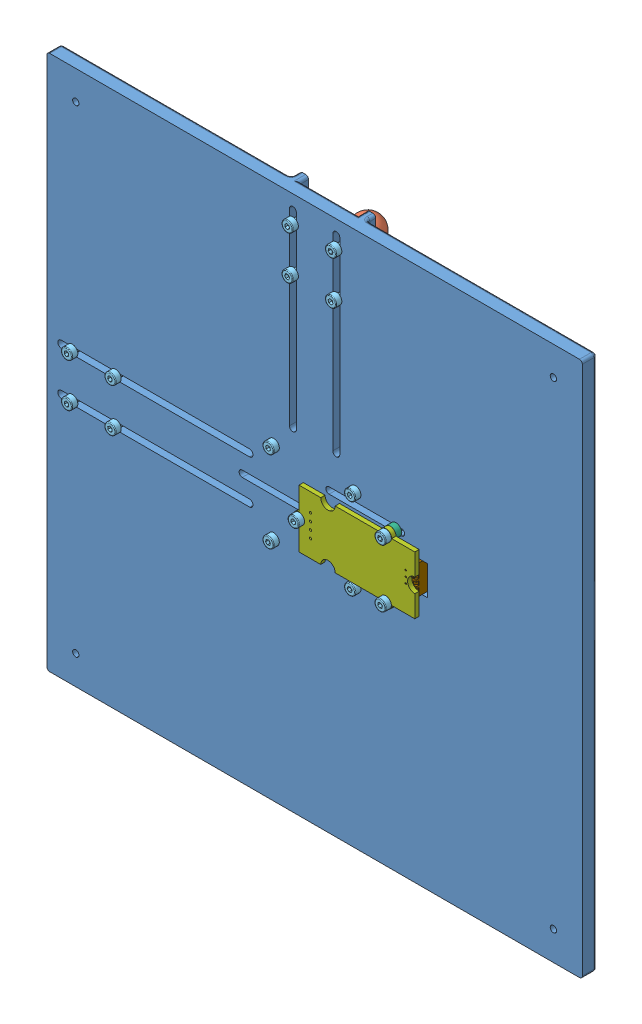
SolidWorks assembly plateau-complet, configuration Défaut. Lengths in mm.
Overall size (185 185 29.5).
45 component instances, 9 part files, 117 mates.
Components (placement in the parent):
- plateau-1: plateau [Défaut] at (22.8083 8.2939 197.5) size (185 185 8)
- support-sphere-ecrou_m2-4: support-sphere-ecrou_m2 [Défaut] at (-53.3917 8.2939 184.1699) x (0 -1 0) z (1 0 0) size (20 18.33 20)
- support-sphere-ecrou_m2-3: support-sphere-ecrou_m2 [Défaut] at (22.8083 84.4939 184.1699) x (1 0 0) z (0 1 0) size (20 18.33 20)
- support-fourchette-ecrou_m2-large-1: support-fourchette-ecrou_m2-large [Défaut] at (22.8083 8.2939 183.5) x (1 0 0) z (0 1 0) size (35 19 35)
- ecrou-h-6: ecrou-h [6007 HU M2] at (30.3083 91.9939 195.1) x (0.866025 -0.5 0) z (-0.5 -0.866025 0) size (4 1.6 4.62)
- ecrou-h-7: ecrou-h [6007 HU M2] at (15.3083 76.9939 195.1) x (0 1 0) z (1 0 0) size (4 1.6 4.62)
- ecrou-h-8: ecrou-h [6007 HU M2] at (30.3083 76.9939 195.1) x (0.866025 0.5 0) z (0.5 -0.866025 0) size (4 1.6 4.62)
- ecrou-h-9: ecrou-h [6007 HU M2] at (15.3083 91.9939 195.1) x (-0.866025 -0.5 0) z (-0.5 0.866025 0) size (4 1.6 4.62)
- ecrou-h-10: ecrou-h [6007 HU M2] at (-60.8917 15.7939 195.1) x (0.5 0.866025 0) z (0.866025 -0.5 0) size (4 1.6 4.62)
- ecrou-h-11: ecrou-h [6007 HU M2] at (-60.8917 0.7939 195.1) x (0.5 0.866025 0) z (0.866025 -0.5 0) size (4 1.6 4.62)
- ecrou-h-12: ecrou-h [6007 HU M2] at (-45.8917 0.7939 195.1) x (-0.5 -0.866025 0) z (-0.866025 0.5 0) size (4 1.6 4.62)
- ecrou-h-13: ecrou-h [6007 HU M2] at (-45.8917 15.7939 195.1) x (-0.5 0.866025 0) z (0.866025 0.5 0) size (4 1.6 4.62)
- vis-chc-15: vis-chc [Vis CHC M2x12] at (-45.8917 0.7939 202.5) x (0.832658 0.553787 0) z (0.553787 -0.832658 0) size (3.8 14 3.8)
- vis-chc-16: vis-chc [Vis CHC M2x12] at (-45.8917 15.7939 202.5) x (0.872712 0.488236 0) z (0.488236 -0.872712 0) size (3.8 14 3.8)
- vis-chc-17: vis-chc [Vis CHC M2x12] at (-60.8917 0.7939 202.5) x (0.878735 -0.477309 0) z (-0.477309 -0.878735 0) size (3.8 14 3.8)
- vis-chc-18: vis-chc [Vis CHC M2x12] at (-60.8917 15.7939 202.5) x (-0.020688 -0.999786 0) z (-0.999786 0.020688 0) size (3.8 14 3.8)
- vis-chc-19: vis-chc [Vis CHC M2x12] at (15.3083 76.9939 202.5) x (-0.459945 -0.887947 0) z (-0.887947 0.459945 0) size (3.8 14 3.8)
- vis-chc-20: vis-chc [Vis CHC M2x12] at (30.3083 76.9939 202.5) x (-0.307246 0.95163 0) z (0.95163 0.307246 0) size (3.8 14 3.8)
- vis-chc-21: vis-chc [Vis CHC M2x12] at (15.3083 91.9939 202.5) x (0.103271 -0.994653 0) z (-0.994653 -0.103271 0) size (3.8 14 3.8)
- vis-chc-22: vis-chc [Vis CHC M2x12] at (30.3083 91.9939 202.5) x (0.948564 0.316586 0) z (0.316586 -0.948564 0) size (3.8 14 3.8)
- vis-chc-23: vis-chc [Vis CHC M2x12] at (8.7083 22.3939 202.5) x (0.719096 0.694911 0) z (0.694911 -0.719096 0) size (3.8 14 3.8)
- vis-chc-24: vis-chc [Vis CHC M2x12] at (36.9083 22.3939 202.5) x (0.587191 0.809448 0) z (0.809448 -0.587191 0) size (3.8 14 3.8)
- vis-chc-25: vis-chc [Vis CHC M2x12] at (8.7083 -5.8061 202.5) x (0.239044 0.971009 0) z (0.971009 -0.239044 0) size (3.8 14 3.8)
- vis-chc-26: vis-chc [Vis CHC M2x12] at (36.9083 -5.8061 202.5) x (0.971464 0.237189 0) z (0.237189 -0.971464 0) size (3.8 14 3.8)
- ecrou-h-14: ecrou-h [6007 HU M2] at (8.7083 22.3939 195.16) x (0.866025 -0.5 0) z (-0.5 -0.866025 0) size (4 1.6 4.62)
- ecrou-h-15: ecrou-h [6007 HU M2] at (8.7083 -5.8061 195.16) x (0.866025 -0.5 0) z (-0.5 -0.866025 0) size (4 1.6 4.62)
- ecrou-h-16: ecrou-h [6007 HU M2] at (36.9083 -5.8061 195.16) x (0.866025 -0.5 0) z (-0.5 -0.866025 0) size (4 1.6 4.62)
- ecrou-h-17: ecrou-h [6007 HU M2] at (36.9083 22.3939 195.16) x (-0.866025 0.5 0) z (0.5 0.866025 0) size (4 1.6 4.62)
- ecrou-h-18: ecrou-h [6007 HU M2] at (-59.6917 90.7939 200.5) x (0.866025 0.5 0) z (0.5 -0.866025 0) size (4 1.6 4.62)
- ecrou-h-19: ecrou-h [6007 HU M2] at (105.3083 90.7939 198.9) x (0.866025 0.5 0) z (-0.5 0.866025 0) size (4 1.6 4.62)
- ecrou-h-20: ecrou-h [6007 HU M2] at (-59.6917 -74.2061 200.5) x (0 -1 0) z (-1 0 0) size (4 1.6 4.62)
- ecrou-h-21: ecrou-h [6007 HU M2] at (105.3083 -74.2061 200.5) x (0 1 0) z (1 0 0) size (4 1.6 4.62)
- vis-chc-30: vis-chc [Vis CHC M2x8] at (50.9161 18.1939 206) x (-0.221467 -0.975168 0) z (-0.975168 0.221467 0) size (3.8 10 3.8)
- vis-chc-32: vis-chc [Vis CHC M2x8] at (50.9161 -1.8061 206) x (-0.923728 -0.383049 0) z (-0.383049 0.923728 0) size (3.8 10 3.8)
- vis-chc-33: vis-chc [Vis CHC M2x8] at (20.9161 8.1939 206) x (-0.787107 -0.616816 0) z (-0.616816 0.787107 0) size (3.8 10 3.8)
- ecrou-h-24: ecrou-h [6007 HU M2] at (20.9161 8.1939 197.9) x (0 -1 0) z (1 0 0) size (4 1.6 4.62)
- ecrou-h-25: ecrou-h [6007 HU M2] at (50.9161 -1.8061 197.9) x (0.866025 0.5 0) z (-0.5 0.866025 0) size (4 1.6 4.62)
- ecrou-h-26: ecrou-h [6007 HU M2] at (50.9161 18.1939 197.9) x (-0.866025 0.5 0) z (-0.5 -0.866025 0) size (4 1.6 4.62)
- entretoise-grove-1: entretoise-grove [Défaut] at (50.9161 18.1939 202.5) x (0.992185 0.124776 0) z (0 0 1) size (4 4 2)
- entretoise-grove-2: entretoise-grove [Défaut] at (20.9161 8.1939 202.5) x (0.16979 0.98548 0) z (0 0 1) size (4 4 2)
- entretoise-grove-3: entretoise-grove [Défaut] at (50.9161 -1.8061 202.5) x (0.064788 0.997899 0) z (0 0 1) size (4 4 2)
- Grove IMU - droit-1: Grove IMU - droit [Défaut] at (42.9373 5.7987 163.25) x (0 -1 0) z (0 0 1) size (24 42 9.5)
  - Grove IMU Board-1: Grove IMU Board [Défaut] at (-2.3952 -22.0212 41.25) size (24 42 1.5)
  - MPU9150-1: MPU9150 [Défaut] at (-3.0078 -7.8003 40.45) size (4 4 0.8)
  - Connecteur Grove - droit-1: Connecteur Grove - droit [Défaut] at (-2.3952 11.9788 41.25) x (-1 0 0) z (0 -1 0) size (10 11 5)
Mates (geometry in assembly coordinates):
- Coïncidente5: coincident anti-aligned: plane of plateau-1 through (22.8083 8.2939 197.5) normal (0 0 -1); plane of support-sphere-ecrou_m2-4 through (-53.3917 8.2939 197.5) normal (0 0 1)
- Coïncidente8: coincident anti-aligned: plane of plateau-1 through (22.8083 8.2939 197.5) normal (0 0 -1); plane of support-sphere-ecrou_m2-3 through (22.8083 84.4939 197.5) normal (0 0 1)
- Coïncidente12: coincident anti-aligned: plane of plateau-1 through (22.8083 8.2939 197.5) normal (0 0 -1); plane of support-fourchette-ecrou_m2-large-1 through (22.8083 8.2939 197.5) normal (0 0 1)
- Coaxiale9: concentric anti-aligned: cylinder of support-sphere-ecrou_m2-3 through (30.3083 91.9939 197.501) axis (0 0 -1) radius 1.1; cylinder of ecrou-h-m2-6 through (30.3083 91.9939 193.5) axis (0 0 1) radius 0.7835
- Coïncidente26: coincident anti-aligned: plane of support-sphere-ecrou_m2-3 through (22.8083 84.4939 195.1) normal (0 0 -1); plane of ecrou-h-m2-6 through (32.6177 91.9939 195.1) normal (0 0 1)
- Parallèle1: parallel anti-aligned: plane of support-sphere-ecrou_m2-3 through (27.9783 91.9939 195.1) normal (0.866025 -0.5 0); plane of ecrou-h-m2-6 through (29.1536 93.9939 193.5) normal (-0.866025 0.5 0)
- Coaxiale10: concentric anti-aligned: cylinder of support-sphere-ecrou_m2-3 through (15.3083 91.9939 197.501) axis (0 0 -1) radius 1.1; cylinder of ecrou-h-m2-9 through (15.3083 91.9939 193.5) axis (0 0 1) radius 0.7835
- Parallèle2: parallel anti-aligned: plane of support-sphere-ecrou_m2-3 through (14.1433 94.0118 195.1) normal (0 -1 0); plane of ecrou-h-m2-9 through (16.463 93.9939 193.5) normal (0 1 0)
- Coïncidente29: coincident anti-aligned: plane of support-sphere-ecrou_m2-3 through (22.8083 84.4939 195.1) normal (0 0 -1); plane of ecrou-h-m2-9 through (16.463 89.9939 195.1) normal (0 0 1)
- Coaxiale11: concentric anti-aligned: cylinder of support-sphere-ecrou_m2-3 through (15.3083 76.9939 197.501) axis (0 0 -1) radius 1.1; cylinder of ecrou-h-m2-7 through (15.3083 76.9939 193.5) axis (0 0 1) radius 0.7835
- Parallèle3: parallel anti-aligned: plane of support-sphere-ecrou_m2-3 through (12.9783 76.9939 195.1) normal (0.866025 -0.5 0); plane of ecrou-h-m2-7 through (14.1536 78.9939 193.5) normal (-0.866025 0.5 0)
- Coïncidente31: coincident anti-aligned: plane of support-sphere-ecrou_m2-3 through (22.8083 84.4939 195.1) normal (0 0 -1); plane of ecrou-h-m2-7 through (14.1536 74.9939 195.1) normal (0 0 1)
- Coaxiale12: concentric anti-aligned: cylinder of support-sphere-ecrou_m2-3 through (30.3083 76.9939 197.501) axis (0 0 -1) radius 1.1; cylinder of ecrou-h-8 through (30.3083 76.9939 193.5) axis (0 0 1) radius 0.7835
- Parallèle4: parallel anti-aligned: plane of support-sphere-ecrou_m2-3 through (32.6383 76.9939 195.1) normal (-0.866025 0.5 0); plane of ecrou-h-m2-8 through (31.463 74.9939 193.5) normal (0.866025 -0.5 0)
- Coïncidente32: coincident anti-aligned: plane of support-sphere-ecrou_m2-3 through (22.8083 84.4939 195.1) normal (0 0 -1); plane of ecrou-h-m2-8 through (31.463 78.9939 195.1) normal (0 0 1)
- Coaxiale13: concentric anti-aligned: cylinder of support-sphere-ecrou_m2-4 through (-60.8917 15.7939 197.501) axis (0 0 -1) radius 1.1; cylinder of ecrou-h-m2-10 through (-60.8917 15.7939 193.5) axis (0 0 1) radius 0.7835
- Coaxiale14: concentric anti-aligned: cylinder of support-sphere-ecrou_m2-4 through (-60.8917 0.7939 197.501) axis (0 0 -1) radius 1.1; cylinder of ecrou-h-m2-11 through (-60.8917 0.7939 193.5) axis (0 0 1) radius 0.7835
- Coaxiale15: concentric anti-aligned: cylinder of support-sphere-ecrou_m2-4 through (-45.8917 0.7939 197.501) axis (0 0 -1) radius 1.1; cylinder of ecrou-h-m2-12 through (-45.8917 0.7939 193.5) axis (0 0 1) radius 0.7835
- Coaxiale16: concentric anti-aligned: cylinder of support-sphere-ecrou_m2-4 through (-45.8917 15.7939 197.501) axis (0 0 -1) radius 1.1; cylinder of ecrou-h-m2-13 through (-45.8917 15.7939 193.5) axis (0 0 1) radius 0.7835
- Parallèle5: parallel anti-aligned: plane of support-sphere-ecrou_m2-4 through (-43.8738 16.9589 195.1) normal (-1 0 0); plane of ecrou-h-m2-13 through (-43.8917 14.6392 193.5) normal (1 0 0)
- Parallèle6: parallel anti-aligned: plane of support-sphere-ecrou_m2-4 through (-58.8738 16.9589 195.1) normal (-1 0 0); plane of ecrou-h-m2-10 through (-58.8917 14.6392 193.5) normal (1 0 0)
- Parallèle7: parallel anti-aligned: plane of support-sphere-ecrou_m2-4 through (-58.8738 -0.3711 195.1) normal (-0.5 0.866025 0); plane of ecrou-h-m2-11 through (-60.8917 -1.5155 193.5) normal (0.5 -0.866025 0)
- Parallèle8: parallel anti-aligned: plane of support-sphere-ecrou_m2-4 through (-43.8738 -0.3711 195.1) normal (-0.5 0.866025 0); plane of ecrou-h-m2-12 through (-45.8917 -1.5155 193.5) normal (0.5 -0.866025 0)
- Coïncidente37: coincident anti-aligned: plane of support-sphere-ecrou_m2-4 through (-53.3917 8.2939 195.1) normal (0 0 -1); plane of ecrou-h-m2-10 through (-60.8917 13.4845 195.1) normal (0 0 1)
- Coïncidente39: coincident anti-aligned: plane of support-sphere-ecrou_m2-4 through (-53.3917 8.2939 195.1) normal (0 0 -1); plane of ecrou-h-m2-11 through (-60.8917 3.1033 195.1) normal (0 0 1)
- Coïncidente40: coincident anti-aligned: plane of support-sphere-ecrou_m2-4 through (-53.3917 8.2939 195.1) normal (0 0 -1); plane of ecrou-h-m2-12 through (-43.8917 -0.3608 195.1) normal (0 0 1)
- Coaxiale17: concentric anti-aligned: cylinder of support-sphere-ecrou_m2-3 through (30.3083 91.9939 197.501) axis (0 0 -1) radius 1.1; cylinder of vis-chc-m2x10-8 through (30.3083 91.9939 190.5) axis (0 0 1) radius 1
- Coaxiale18: concentric anti-aligned: cylinder of support-sphere-ecrou_m2-3 through (15.3083 91.9939 197.501) axis (0 0 -1) radius 1.1; cylinder of vis-chc-m2x10-9 through (15.3083 91.9939 190.5) axis (0 0 1) radius 1
- Coaxiale19: concentric anti-aligned: cylinder of support-sphere-ecrou_m2-3 through (30.3083 76.9939 197.501) axis (0 0 -1) radius 1.1; cylinder of vis-chc-m2x10-11 through (30.3083 76.9939 190.5) axis (0 0 1) radius 1
- Coaxiale20: concentric anti-aligned: cylinder of support-sphere-ecrou_m2-3 through (15.3083 76.9939 197.501) axis (0 0 -1) radius 1.1; cylinder of vis-chc-m2x10-10 through (15.3083 76.9939 190.5) axis (0 0 1) radius 1
- Coaxiale21: concentric anti-aligned: cylinder of support-sphere-ecrou_m2-4 through (-45.8917 0.7939 197.501) axis (0 0 -1) radius 1.1; cylinder of vis-chc-m2-15 through (-45.8917 0.7939 190.5) axis (0 0 1) radius 1
- Coaxiale22: concentric anti-aligned: cylinder of support-sphere-ecrou_m2-4 through (-60.8917 0.7939 197.501) axis (0 0 -1) radius 1.1; cylinder of vis-chc-m2-17 through (-60.8917 0.7939 190.5) axis (0 0 1) radius 1
- Coaxiale23: concentric anti-aligned: cylinder of support-sphere-ecrou_m2-4 through (-60.8917 15.7939 197.501) axis (0 0 -1) radius 1.1; cylinder of vis-chc-m2-18 through (-60.8917 15.7939 190.5) axis (0 0 1) radius 1
- Coaxiale24: concentric anti-aligned: cylinder of support-sphere-ecrou_m2-4 through (-45.8917 15.7939 197.501) axis (0 0 -1) radius 1.1; cylinder of vis-chc-m2-16 through (-45.8917 15.7939 190.5) axis (0 0 1) radius 1
- Coïncidente41: coincident anti-aligned: plane of plateau-1 through (22.8083 8.2939 202.5) normal (0 0 1); plane of vis-chc-m2x10-10 through (15.3083 76.9939 202.5) normal (0 0 -1)
- Coïncidente42: coincident anti-aligned: plane of plateau-1 through (22.8083 8.2939 202.5) normal (0 0 1); plane of vis-chc-m2x10-9 through (15.3083 91.9939 202.5) normal (0 0 -1)
- Coïncidente43: coincident anti-aligned: plane of plateau-1 through (22.8083 8.2939 202.5) normal (0 0 1); plane of vis-chc-m2x10-8 through (30.3083 91.9939 202.5) normal (0 0 -1)
- Coïncidente44: coincident anti-aligned: plane of plateau-1 through (22.8083 8.2939 202.5) normal (0 0 1); plane of vis-chc-m2x10-11 through (30.3083 76.9939 202.5) normal (0 0 -1)
- Coïncidente45: coincident anti-aligned: plane of plateau-1 through (22.8083 8.2939 202.5) normal (0 0 1); plane of vis-chc-m2-17 through (-60.8917 0.7939 202.5) normal (0 0 -1)
- Coïncidente46: coincident anti-aligned: plane of plateau-1 through (22.8083 8.2939 202.5) normal (0 0 1); plane of vis-chc-m2-15 through (-45.8917 0.7939 202.5) normal (0 0 -1)
- Coïncidente47: coincident anti-aligned: plane of plateau-1 through (22.8083 8.2939 202.5) normal (0 0 1); plane of vis-chc-m2-16 through (-45.8917 15.7939 202.5) normal (0 0 -1)
- Coïncidente48: coincident anti-aligned: plane of plateau-1 through (22.8083 8.2939 202.5) normal (0 0 1); plane of vis-chc-m2-18 through (-60.8917 15.7939 202.5) normal (0 0 -1)
- Distance6: distance = 13.8 mm: cylinder of support-sphere-ecrou_m2-4 through (-53.3917 8.2939 193.5) axis (0 0 1) radius 2.5; plane of plateau-1 through (-69.6917 100.7939 202.5) normal (-1 0 0)
- Distance7: distance = 13.8 mm: cylinder of support-sphere-ecrou_m2-3 through (22.8083 84.4939 193.5) axis (0 0 1) radius 2.5; plane of plateau-1 through (-69.6917 100.7939 202.5) normal (0 1 0)
- Coaxiale25: concentric anti-aligned: cylinder of support-fourchette-ecrou_m2-large-1 through (36.9083 22.3939 197.501) axis (0 0 -1) radius 1.1; cylinder of ecrou-h-m2-17 through (36.9083 22.3939 193.56) axis (0 0 1) radius 0.7835
- Parallèle9: parallel anti-aligned: plane of support-fourchette-ecrou_m2-large-1 through (35.6583 24.559 195.16) normal (0 -1 0); plane of ecrou-h-m2-17 through (38.063 24.3939 193.56) normal (0 1 0)
- Coïncidente50: coincident anti-aligned: plane of support-fourchette-ecrou_m2-large-1 through (22.8083 8.2939 195.16) normal (0 0 -1); plane of ecrou-h-m2-17 through (34.5989 22.3939 195.16) normal (0 0 1)
- Coaxiale26: concentric anti-aligned: cylinder of support-fourchette-ecrou_m2-large-1 through (36.9083 -5.8061 197.501) axis (0 0 -1) radius 1.1; cylinder of ecrou-h-m2-16 through (36.9083 -5.8061 193.56) axis (0 0 1) radius 0.7835
- Coïncidente51: coincident anti-aligned: plane of support-fourchette-ecrou_m2-large-1 through (22.8083 8.2939 195.16) normal (0 0 -1); plane of ecrou-h-m2-16 through (39.2177 -5.8061 195.16) normal (0 0 1)
- Parallèle10: parallel anti-aligned: plane of support-fourchette-ecrou_m2-large-1 through (35.6583 -3.641 195.16) normal (0 -1 0); plane of ecrou-h-m2-16 through (38.063 -3.8061 193.56) normal (0 1 0)
- Coaxiale27: concentric anti-aligned: cylinder of support-fourchette-ecrou_m2-large-1 through (8.7083 -5.8061 197.501) axis (0 0 -1) radius 1.1; cylinder of ecrou-h-m2-15 through (8.7083 -5.8061 193.56) axis (0 0 1) radius 0.7835
- Parallèle11: parallel anti-aligned: plane of support-fourchette-ecrou_m2-large-1 through (9.9583 -7.9711 195.16) normal (0 1 0); plane of ecrou-h-m2-15 through (7.5536 -7.8061 193.56) normal (0 -1 0)
- Coïncidente54: coincident anti-aligned: plane of support-fourchette-ecrou_m2-large-1 through (22.8083 8.2939 195.16) normal (0 0 -1); plane of ecrou-h-m2-15 through (11.0177 -5.8061 195.16) normal (0 0 1)
- Coaxiale28: concentric anti-aligned: cylinder of support-fourchette-ecrou_m2-large-1 through (8.7083 22.3939 197.501) axis (0 0 -1) radius 1.1; cylinder of ecrou-h-m2-14 through (8.7083 22.3939 193.56) axis (0 0 1) radius 0.7835
- Parallèle12: parallel anti-aligned: plane of support-fourchette-ecrou_m2-large-1 through (7.4583 24.559 195.16) normal (0 -1 0); plane of ecrou-h-m2-14 through (9.863 24.3939 193.56) normal (0 1 0)
- Coïncidente56: coincident anti-aligned: plane of support-fourchette-ecrou_m2-large-1 through (22.8083 8.2939 195.16) normal (0 0 -1); plane of ecrou-h-m2-14 through (11.0177 22.3939 195.16) normal (0 0 1)
- Coaxiale29: concentric anti-aligned: cylinder of plateau-1 through (8.7083 -5.8061 202.501) axis (0 0 -1) radius 1.1; cylinder of vis-chc-m2-25 through (8.7083 -5.8061 190.5) axis (0 0 1) radius 1
- Coïncidente57: coincident anti-aligned: plane of plateau-1 through (22.8083 8.2939 202.5) normal (0 0 1); plane of vis-chc-m2-25 through (8.7083 -5.8061 202.5) normal (0 0 -1)
- Coaxiale30: concentric anti-aligned: cylinder of plateau-1 through (36.9083 -5.8061 202.501) axis (0 0 -1) radius 1.1; cylinder of vis-chc-26 through (36.9083 -5.8061 190.5) axis (0 0 1) radius 1
- Coïncidente58: coincident anti-aligned: plane of plateau-1 through (22.8083 8.2939 202.5) normal (0 0 1); plane of vis-chc-26 through (36.9083 -5.8061 202.5) normal (0 0 -1)
- Coaxiale31: concentric anti-aligned: cylinder of plateau-1 through (8.7083 22.3939 202.501) axis (0 0 -1) radius 1.1; cylinder of vis-chc-m2-23 through (8.7083 22.3939 190.5) axis (0 0 1) radius 1
- Coïncidente59: coincident anti-aligned: plane of plateau-1 through (22.8083 8.2939 202.5) normal (0 0 1); plane of vis-chc-m2-23 through (8.7083 22.3939 202.5) normal (0 0 -1)
- Coaxiale32: concentric anti-aligned: cylinder of plateau-1 through (36.9083 22.3939 202.501) axis (0 0 -1) radius 1.1; cylinder of vis-chc-m2-24 through (36.9083 22.3939 190.5) axis (0 0 1) radius 1
- Coïncidente60: coincident anti-aligned: plane of plateau-1 through (22.8083 8.2939 202.5) normal (0 0 1); plane of vis-chc-m2-24 through (36.9083 22.3939 202.5) normal (0 0 -1)
- Coaxiale33: concentric anti-aligned: cylinder of plateau-1 through (105.3083 90.7939 202.501) axis (0 0 -1) radius 1.1; circle of ecrou-h-m2-19
- Coaxiale34: concentric anti-aligned: cylinder of plateau-1 through (-59.6917 90.7939 202.501) axis (0 0 -1) radius 1.1; cylinder of ecrou-h-18 through (-59.6917 90.7939 198.9) axis (0 0 1) radius 0.7835
- Coaxiale35: concentric anti-aligned: cylinder of plateau-1 through (-59.6917 -74.2061 202.501) axis (0 0 -1) radius 1.1; cylinder of ecrou-h-20 through (-59.6917 -74.2061 198.9) axis (0 0 1) radius 0.7835
- Coaxiale36: concentric anti-aligned: cylinder of plateau-1 through (105.3083 -74.2061 202.501) axis (0 0 -1) radius 1.1; cylinder of ecrou-h-21 through (105.3083 -74.2061 198.9) axis (0 0 1) radius 0.7835
- Coaxiale37: concentric aligned: cylinder of ecrou-h-m2-16 through (36.9083 -5.8061 193.56) axis (0 0 1) radius 0.7835; cylinder of vis-chc-26 through (36.9083 -5.8061 190.5) axis (0 0 1) radius 1
- Coaxiale38: concentric aligned: cylinder of ecrou-h-m2-14 through (8.7083 22.3939 193.56) axis (0 0 1) radius 0.7835; cylinder of vis-chc-m2-23 through (8.7083 22.3939 190.5) axis (0 0 1) radius 1
- Parallèle13: parallel aligned: plane of plateau-1 through (-69.6917 100.7939 202.5) normal (0 1 0); plane of support-sphere-ecrou_m2-3 through (12.8083 94.4939 197.5) normal (0 1 0)
- Distance8: distance = 0.1 mm anti-aligned: plane of support-sphere-ecrou_m2-3 through (12.8083 94.4939 197.5) normal (-1 0 0); plane of plateau-1 through (12.7083 30.7939 194.5) normal (1 0 0)
- Parallèle14: parallel aligned: plane of plateau-1 through (-69.6917 100.7939 202.5) normal (-1 0 0); plane of support-sphere-ecrou_m2-4 through (-63.3917 18.2939 197.5) normal (-1 0 0)
- Distance9: distance = 0.1 mm anti-aligned: plane of support-sphere-ecrou_m2-4 through (-43.3917 18.2939 197.5) normal (0 1 0); plane of plateau-1 through (0.3083 18.3939 194.5) normal (0 -1 0)
- Parallèle15: parallel aligned: plane of plateau-1 through (115.3083 100.7939 202.5) normal (1 0 0); plane of Grove IMU - droit-1/Grove IMU Board-1 through (60.9161 -1.8061 206) normal (1 0 0)
- Tangent1: tangent anti-aligned: plane of plateau-1 through (27.8083 -2.8061 194.499) normal (0 1 0); cylinder of Grove IMU - droit-1/Grove IMU Board-1 through (50.9161 -1.8061 204.5) axis (0 0 1) radius 1
- Distance10: distance = 2 mm anti-aligned: plane of Grove IMU - droit-1/Grove IMU Board-1 through (30.9161 18.1939 204.5) normal (0 0 -1); plane of plateau-1 through (22.8083 8.2939 202.5) normal (0 0 1)
- Coaxiale45: concentric aligned: cylinder of Grove IMU - droit-1/Grove IMU Board-1 through (50.9161 18.1939 204.5) axis (0 0 1) radius 1; cylinder of vis-chc-30 through (50.9161 18.1939 198) axis (0 0 1) radius 1
- Coïncidente70: coincident anti-aligned: plane of Grove IMU - droit-1/Grove IMU Board-1 through (30.9161 18.1939 206) normal (0 0 1); plane of vis-chc-30 through (50.9161 18.1939 206) normal (0 0 -1)
- Coaxiale46: concentric anti-aligned: cylinder of vis-chc-30 through (50.9161 18.1939 198) axis (0 0 1) radius 1; cylinder of ecrou-h-26 through (50.9161 18.1939 199.5) axis (0 0 -1) radius 0.7835
- Parallèle18: parallel anti-aligned: plane of plateau-1 through (55.8083 20.3939 199.5) normal (0 -1 0); plane of ecrou-h-26 through (49.7614 20.1939 199.5) normal (0 1 0)
- Coïncidente72: coincident anti-aligned: plane of plateau-1 through (22.8083 8.2939 199.5) normal (0 0 -1); plane of ecrou-h-26 through (49.7614 20.1939 199.5) normal (0 0 1)
- Coaxiale47: concentric aligned: cylinder of Grove IMU - droit-1/Grove IMU Board-1 through (50.9161 -1.8061 204.5) axis (0 0 1) radius 1; cylinder of vis-chc-32 through (50.9161 -1.8061 198) axis (0 0 1) radius 1
- Coaxiale48: concentric aligned: cylinder of Grove IMU - droit-1/Grove IMU Board-1 through (20.9161 8.1939 204.5) axis (0 0 1) radius 1; cylinder of vis-chc-33 through (20.9161 8.1939 198) axis (0 0 1) radius 1
- Coïncidente73: coincident anti-aligned: plane of Grove IMU - droit-1/Grove IMU Board-1 through (30.9161 18.1939 206) normal (0 0 1); plane of vis-chc-32 through (50.9161 -1.8061 206) normal (0 0 -1)
- Coïncidente74: coincident anti-aligned: plane of Grove IMU - droit-1/Grove IMU Board-1 through (30.9161 18.1939 206) normal (0 0 1); plane of vis-chc-33 through (20.9161 8.1939 206) normal (0 0 -1)
- Coaxiale50: concentric anti-aligned: cylinder of vis-chc-32 through (50.9161 -1.8061 198) axis (0 0 1) radius 1; cylinder of ecrou-h-25 through (50.9161 -1.8061 199.5) axis (0 0 -1) radius 0.7835
- Parallèle19: parallel anti-aligned: plane of plateau-1 through (55.8083 0.3939 199.5) normal (0 -1 0); plane of ecrou-h-25 through (49.7614 0.1939 199.5) normal (0 1 0)
- Coïncidente76: coincident anti-aligned: plane of plateau-1 through (22.8083 8.2939 199.5) normal (0 0 -1); plane of ecrou-h-25 through (53.2255 -1.8061 199.5) normal (0 0 1)
- Coaxiale51: concentric anti-aligned: cylinder of vis-chc-33 through (20.9161 8.1939 198) axis (0 0 1) radius 1; cylinder of ecrou-h-24 through (20.9161 8.1939 199.5) axis (0 0 -1) radius 0.7835
- Parallèle20: parallel anti-aligned: plane of plateau-1 through (25.8083 10.3939 199.5) normal (0 -1 0); plane of ecrou-h-24 through (19.7614 10.1939 199.5) normal (0 1 0)
- Coïncidente78: coincident anti-aligned: plane of plateau-1 through (22.8083 8.2939 199.5) normal (0 0 -1); plane of ecrou-h-24 through (19.7614 6.1939 199.5) normal (0 0 1)
- Coaxiale52: concentric anti-aligned: cylinder of vis-chc-32 through (50.9161 -1.8061 198) axis (0 0 1) radius 1; cylinder of entretoise-grove-3 through (50.9161 -1.8061 204.5) axis (0 0 -1) radius 1
- Coïncidente79: coincident anti-aligned: plane of plateau-1 through (22.8083 8.2939 202.5) normal (0 0 1); plane of entretoise-grove-3 through (50.9161 -1.8061 202.5) normal (0 0 -1)
- Coaxiale53: concentric anti-aligned: cylinder of vis-chc-30 through (50.9161 18.1939 198) axis (0 0 1) radius 1; cylinder of entretoise-grove-1 through (50.9161 18.1939 204.5) axis (0 0 -1) radius 1
- Coïncidente80: coincident anti-aligned: plane of plateau-1 through (22.8083 8.2939 202.5) normal (0 0 1); plane of entretoise-grove-1 through (50.9161 18.1939 202.5) normal (0 0 -1)
- Coaxiale54: concentric anti-aligned: cylinder of vis-chc-33 through (20.9161 8.1939 198) axis (0 0 1) radius 1; cylinder of entretoise-grove-2 through (20.9161 8.1939 204.5) axis (0 0 -1) radius 1
- Coïncidente81: coincident anti-aligned: plane of plateau-1 through (22.8083 8.2939 202.5) normal (0 0 1); plane of entretoise-grove-2 through (20.9161 8.1939 202.5) normal (0 0 -1)
- Parallèle21: parallel anti-aligned: plane of support-fourchette-ecrou_m2-large-1 through (9.9583 24.559 195.16) normal (-0.866025 -0.5 0); plane of ecrou-h-14 through (11.0177 22.3939 193.56) normal (0.866025 0.5 0)
- Parallèle22: parallel anti-aligned: plane of support-fourchette-ecrou_m2-large-1 through (6.2083 -5.8061 195.16) normal (0.866025 -0.5 0); plane of ecrou-h-15 through (7.5536 -3.8061 193.56) normal (-0.866025 0.5 0)
- Parallèle23: parallel anti-aligned: plane of support-fourchette-ecrou_m2-large-1 through (34.4083 22.3939 195.16) normal (0.866025 -0.5 0); plane of ecrou-h-17 through (35.7536 24.3939 193.56) normal (-0.866025 0.5 0)
- Coïncidente85: coincident anti-aligned: plane of support-sphere-ecrou_m2-4 through (-53.3917 8.2939 195.1) normal (0 0 -1); plane of ecrou-h-12 through (-45.8917 -1.5155 195.1) normal (0 0 1)
- Coïncidente86: coincident anti-aligned: plane of support-sphere-ecrou_m2-4 through (-53.3917 8.2939 195.1) normal (0 0 -1); plane of ecrou-h-11 through (-60.8917 3.1033 195.1) normal (0 0 1)
- Coïncidente87: coincident anti-aligned: plane of support-sphere-ecrou_m2-4 through (-53.3917 8.2939 195.1) normal (0 0 -1); plane of ecrou-h-13 through (-47.8917 16.9486 195.1) normal (0 0 1)
- Coïncidente88: coincident anti-aligned: plane of support-sphere-ecrou_m2-4 through (-53.3917 8.2939 195.1) normal (0 0 -1); plane of ecrou-h-10 through (-60.8917 18.1033 195.1) normal (0 0 1)
- Parallèle24: parallel anti-aligned: plane of support-sphere-ecrou_m2-4 through (-45.8917 13.2939 195.1) normal (-0.5 0.866025 0); plane of ecrou-h-13 through (-45.8917 13.4845 193.5) normal (0.5 -0.866025 0)
- Parallèle25: parallel anti-aligned: plane of support-sphere-ecrou_m2-4 through (-48.0567 2.0439 195.1) normal (0.5 -0.866025 0); plane of ecrou-h-12 through (-45.8917 3.1033 193.5) normal (-0.5 0.866025 0)
- Parallèle26: parallel anti-aligned: plane of support-sphere-ecrou_m2-4 through (-60.8917 3.2939 195.1) normal (0.5 -0.866025 0); plane of ecrou-h-11 through (-60.8917 3.1033 193.5) normal (-0.5 0.866025 0)
- Parallèle27: parallel anti-aligned: plane of support-sphere-ecrou_m2-4 through (-60.8917 13.2939 195.1) normal (-0.5 0.866025 0); plane of ecrou-h-10 through (-60.8917 13.4845 193.5) normal (0.5 -0.866025 0)
- Coïncidente93: coincident anti-aligned: plane of support-sphere-ecrou_m2-3 through (22.8083 84.4939 195.1) normal (0 0 -1); plane of ecrou-h-7 through (14.1536 78.9939 195.1) normal (0 0 1)
- Coïncidente94: coincident anti-aligned: plane of support-sphere-ecrou_m2-3 through (22.8083 84.4939 195.1) normal (0 0 -1); plane of ecrou-h-8 through (31.463 78.9939 195.1) normal (0 0 1)
- Coïncidente95: coincident anti-aligned: plane of support-sphere-ecrou_m2-3 through (22.8083 84.4939 195.1) normal (0 0 -1); plane of ecrou-h-6 through (32.6177 91.9939 195.1) normal (0 0 1)
- Coïncidente96: coincident anti-aligned: plane of support-sphere-ecrou_m2-3 through (22.8083 84.4939 195.1) normal (0 0 -1); plane of ecrou-h-9 through (14.1536 89.9939 195.1) normal (0 0 1)
- Parallèle28: parallel anti-aligned: plane of support-sphere-ecrou_m2-3 through (17.8083 91.9939 195.1) normal (-0.866025 -0.5 0); plane of ecrou-h-9 through (17.6177 91.9939 193.5) normal (0.866025 0.5 0)
- Parallèle29: parallel anti-aligned: plane of support-sphere-ecrou_m2-3 through (27.8083 91.9939 195.1) normal (0.866025 -0.5 0); plane of ecrou-h-6 through (29.1536 93.9939 193.5) normal (-0.866025 0.5 0)
- Parallèle30: parallel anti-aligned: plane of support-sphere-ecrou_m2-3 through (16.5583 79.159 195.1) normal (0 -1 0); plane of ecrou-h-7 through (16.463 78.9939 193.5) normal (0 1 0)
- Parallèle31: parallel anti-aligned: plane of support-sphere-ecrou_m2-3 through (35.5562 79.159 195.1) normal (0 -1 0); plane of ecrou-h-8 through (31.463 78.9939 193.5) normal (0 1 0)
